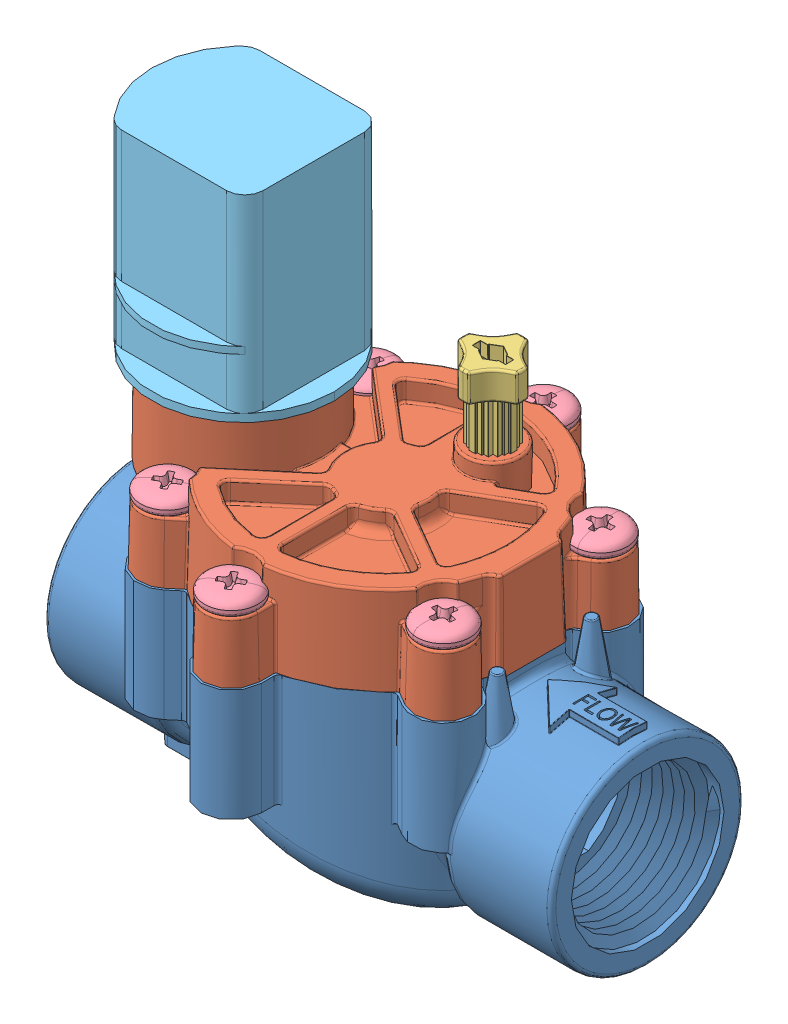
SolidWorks assembly DV100, configuration Domyślna. Lengths in mm.
Overall size (113 119.31 84.45).
12 component instances, 6 part files, 0 mates.
Components (placement in the parent):
- DV100.STEP-1: DV100.STEP [Domyślna] at origin size (113 119.31 84.45)
  - main body_D_faut.STEP-1: main body_D_faut.STEP [Domyślna] at origin size (113 52 82.96)
  - top body_D_faut.STEP-1: top body_D_faut.STEP [Domyślna] at (0 25 0) size (85.88 28.46 82)
  - debit adjust screw_D_faut.STEP-1: debit adjust screw_D_faut.STEP [Domyślna] at (8.5939 64.878 -14.9568) size (13.46 27.18 13.46)
  - SS screw_D_faut.STEP-1: SS screw_D_faut.STEP [Domyślna] at (30.0219 38.335 -17.5) x (0.990926 0 -0.134407) z (0.134407 0 0.990926) size (11.91 34.68 11.91)
  - SS screw_D_faut.STEP-2: SS screw_D_faut.STEP [Domyślna] at (0 38.335 -34.75) x (0.999934 0 -0.011508) z (0.011508 0 0.999934) size (11.91 34.68 11.91)
  - SS screw_D_faut.STEP-3: SS screw_D_faut.STEP [Domyślna] at (-26.4823 38.335 -22.5) x (0.983354 0 0.1817) z (-0.1817 0 0.983354) size (11.91 34.68 11.91)
  - SS screw_D_faut.STEP-4: SS screw_D_faut.STEP [Domyślna] at (0 38.335 34.75) x (0.536421 0 0.84395) z (-0.84395 0 0.536421) size (11.91 34.68 11.91)
  - SS screw_D_faut.STEP-5: SS screw_D_faut.STEP [Domyślna] at (-26.4823 38.335 22.5) x (0.504146 0 0.863619) z (-0.863619 0 0.504146) size (11.91 34.68 11.91)
  - SS screw_D_faut.STEP-6: SS screw_D_faut.STEP [Domyślna] at (30.0219 38.335 17.5) x (0.989719 0 0.143023) z (-0.143023 0 0.989719) size (11.91 34.68 11.91)
  - solenoid.STEP-1: solenoid.STEP [Domyślna] at (-32.109 54.591 0) x (0 0 1) z (-1 0 0) size (40.64 59.44 40.64)
  - SS screw.STEP-1: SS screw.STEP [Domyślna] at (-32.109 47.225 0) x (-0.479815 0 -0.87737) z (0.87737 0 -0.479815) size (26.92 1.78 26.92)
